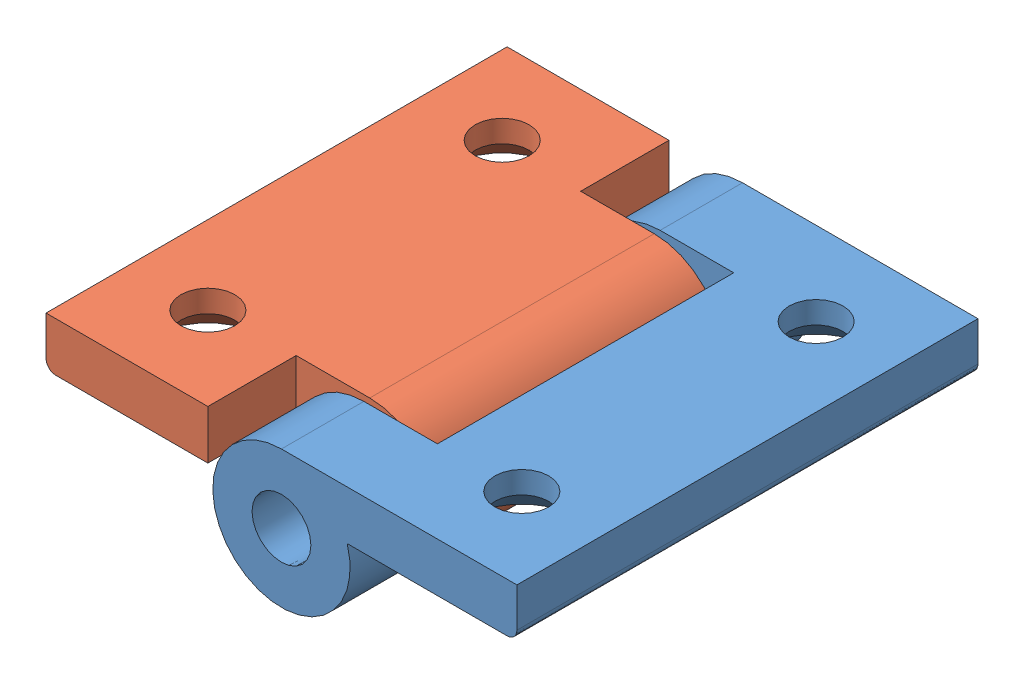
SolidWorks assembly Hinge, configuration Default. Lengths in mm.
Overall size (48 14 47).
2 component instances, 2 part files, 4 mates.
Components (placement in the parent):
- _SHHPSZ6-l-1: _SHHPSZ6-l [Default] at (0 -7 0) x (-1 0 0) z (0 -1 0) size (31 47 14)
- _SHHPSZ6-r-1: _SHHPSZ6-r [Default] at (0 -7 0) x (-1 0 0) z (0 -1 0) size (31 47 14)
Mates (geometry in assembly coordinates):
- Coincident3: coincident aligned: plane of _SHHPSZ6-l-1 through (0 0 0) normal (0 1 0); plane of assembly through (0 0 0) normal (0 1 0)
- Hinge1: hinge = 0 rad aligned: cylinder of _SHHPSZ6-r-1 through (0 -7 23.5) axis (0 0 -1) radius 3; cylinder of _SHHPSZ6-l-1 through (0 -7 23.5) axis (0 0 -1) radius 3; plane of _SHHPSZ6-r-1 through (0 -7 -23.5) normal (0 0 -1); plane of _SHHPSZ6-l-1 through (0 -7 -23.5) normal (0 0 -1); plane of _SHHPSZ6-r-1 through (0 0 0) normal (0 1 0); plane of _SHHPSZ6-l-1 through (0 0 0) normal (0 1 0)
- Coincident7: coincident anti-aligned: plane of _SHHPSZ6-l-1 through (0 -7 0) normal (0 0 -1); plane of assembly through (0 0 0) normal (0 0 1)
- Coincident8: coincident anti-aligned: plane of _SHHPSZ6-l-1 through (0 -7 0) normal (-1 0 0); plane of assembly through (0 0 0) normal (1 0 0)
